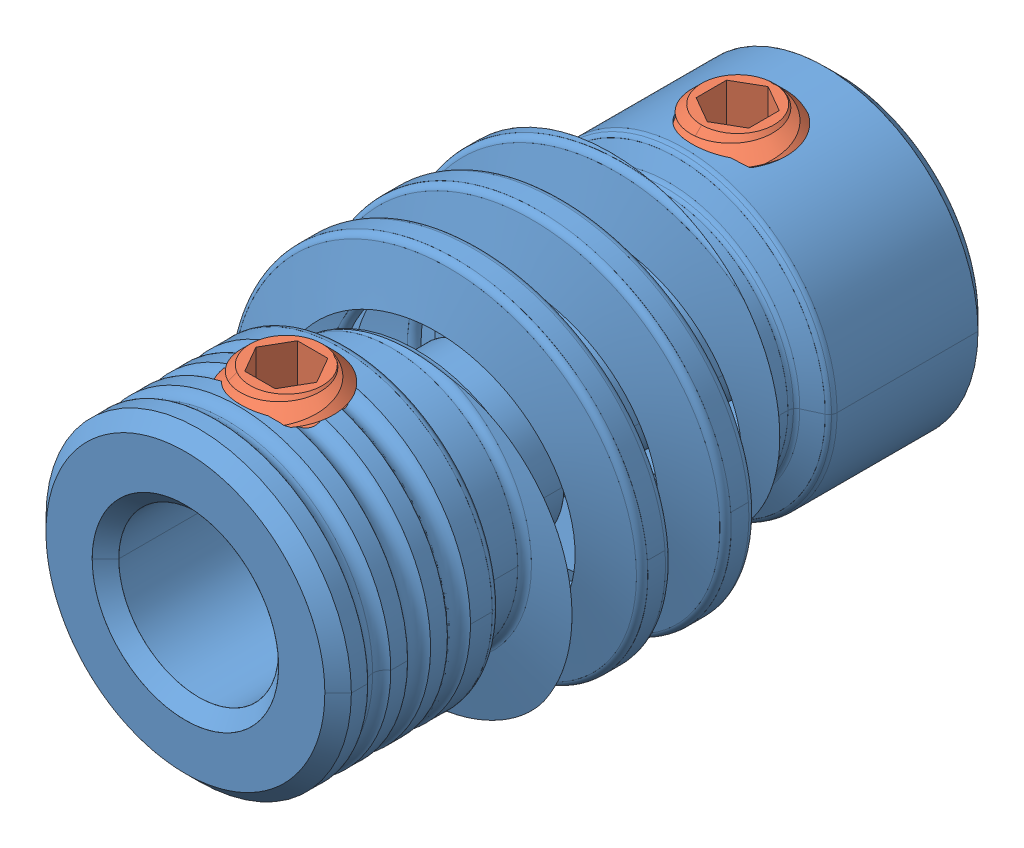
SolidWorks assembly Tetrix Worm Screw (20 to 1), configuration Default. Lengths in mm.
Overall size (43.76 43.76 43.76).
3 component instances, 2 part files, 0 mates.
Components (placement in the parent):
- Tetrix Worm Screw (20 to 1) Body-1: Tetrix Worm Screw (20 to 1) Body [Default] at origin size (43.76 43.76 43.76)
- Tetrix Worm Screw (20 to 1) Set Screw-1: Tetrix Worm Screw (20 to 1) Set Screw [Default] at (0 3.01 8.5) x (0.866025 0 0.5) z (-0.5 0 0.866025) size (4.08 3.31 3.99)
- Tetrix Worm Screw (20 to 1) Set Screw-2: Tetrix Worm Screw (20 to 1) Set Screw [Default] at (0 3.01 -8.5) size (4.08 3.31 3.99)
